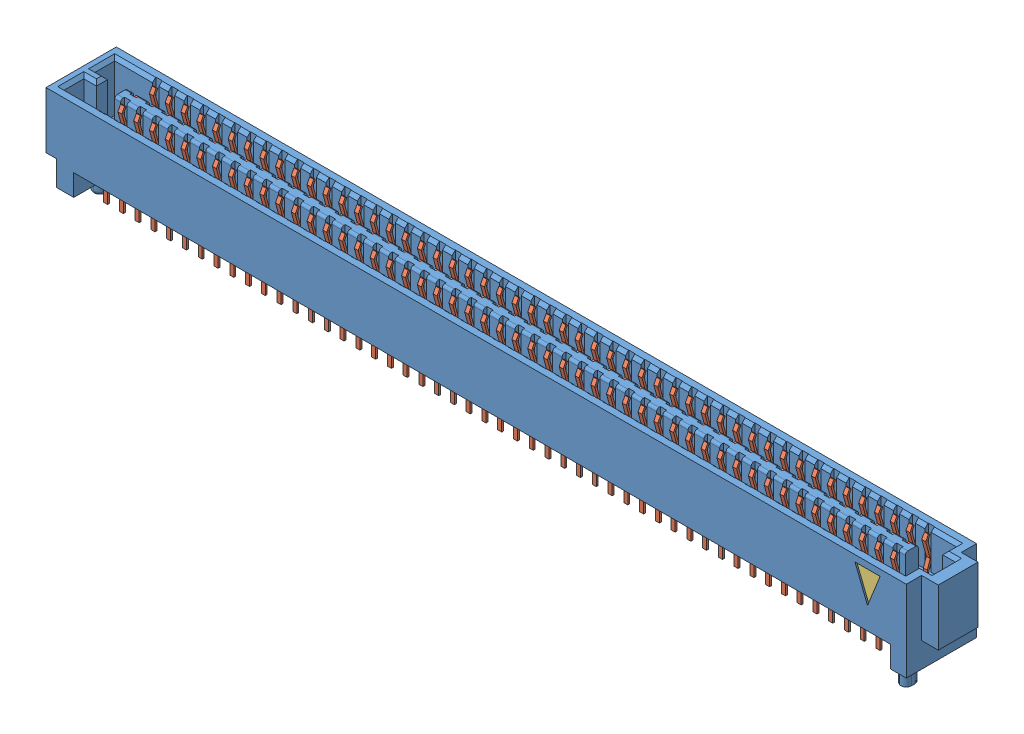
SolidWorks assembly SEAF_50_06_5_L_04_2_A_K_TR, configuration Default. Lengths in mm.
Overall size (70.66 7.82 5.66).
4 component instances, 4 part files, 0 mates.
Components (placement in the parent):
- _SEAF_50_06_5_L_04_1_A_0_K_TR_BODY_2_2-1: _SEAF_50_06_5_L_04_1_A_0_K_TR_BODY_2_2 [Default] at origin size (70.66 7.82 5.66)
- _SEAF_50_06_5_L_04_1_A_0_K_TR_cCON2_4-1: _SEAF_50_06_5_L_04_1_A_0_K_TR_cCON2_4 [Default] at origin size (62.55 6.17 5.41)
- _SEAF_04_K_PAD_6-1: _SEAF_04_K_PAD_6 [Default] at (-0.2286 4.826 0) size (6.5 0.13 6.5) (hidden)
- _SEAF_TRIANGLE_FIRST_PIN_8-1: _SEAF_TRIANGLE_FIRST_PIN_8 [Default] at (30.861 1.27 2.5781) size (2.03 2.54 0.13)
